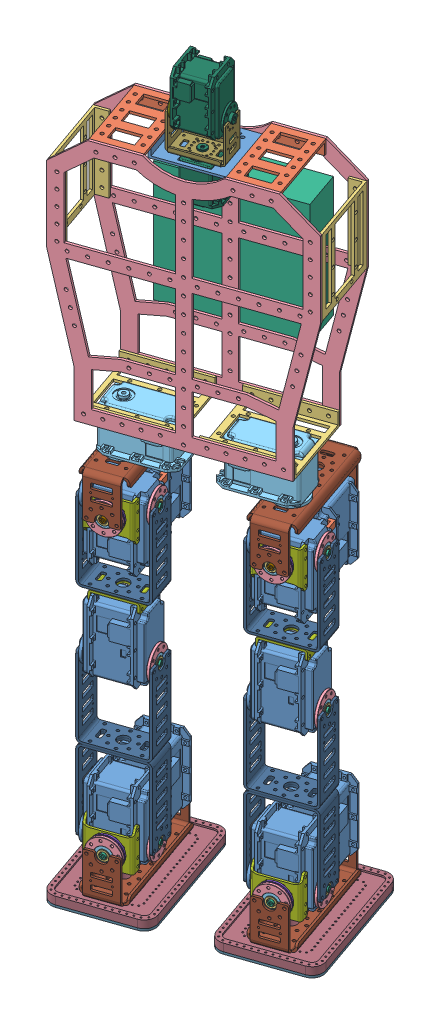
SolidWorks assembly main_new_feet_no_arm, configuration Default. Lengths in mm.
Overall size (261.31 695.74 185.95).
113 component instances, 25 part files, 43 mates.
Components (placement in the parent):
- leg_l2-1: leg_l2 [Default] at (32.8984 -224.9307 -176.674) x (0.329122 0 0.944287) z (-0.944287 0 0.329122) size (106.88 70.06 58.88)
  - MX-106T_step-1: MX-106T_step [Default] at origin size (40.2 65.92 55.3)
  - MX-106T_step-2: MX-106T_step [Default] at (-44 0 0) x (0 0 1) z (-1 0 0) size (40.2 65.92 55.3)
  - FR08-X101_2017-1: FR08-X101_2017 [Default] at (-27 -7 -17) x (0 -1 0) z (0 0 1) size (28 12.3 4.8)
  - FR08-X101_2017-2: FR08-X101_2017 [Default] at (-27 -7 17) x (0 1 0) z (0 0 -1) size (28 12.3 4.8)
  - RX64-CAP_2017-1: RX64-CAP_2017 [Default] at (0 0 -25.78) x (0.56381 0.825904 0) z (0 0 -1) size (9.5 9.5 2.2)
  - HN05-I101_2017-1: HN05-I101_2017 [Default] at (0 0 -26.02) x (0.824833 -0.565376 0) z (0.565376 0.824833 0) size (28 3.77 28)
  - MF128ZZ_2017-1: MF128ZZ_2017 [Default] at (0 0 -22.3) x (-0.923728 -0.383049 0) z (0.383049 -0.923728 0) size (14 3.48 14)
  - WB_M2.5X8_2017-1: WB_M2.5X8_2017 [Default] at (0 0 -28.08) x (0 0 1) z (0.825904 -0.56381 0) size (5.5 4.5 4.5)
  - FR05-S101_2017-1: FR05-S101_2017 [Default] at (24 0 0) x (0 1 0) z (0 0 1) size (36 9.31 38.02)
  - FR05-F101_2017-1: FR05-F101_2017 [Default] at (24 0 0) x (0 -0.707107 0.707107) z (1 0 0) size (27 27 5)
  - MF128ZZ_2017-2: MF128ZZ_2017 [Default] at (26.3 0 0) x (0 -1 0) z (0 0 1) size (14 3.48 14)
  - WB_M2.5X8_step-1: WB_M2.5X8_step [Default] at (32.08 0 0) x (-1 0 0) z (0 0.546944 0.837169) size (10.5 4.5 4.5)
  - HN05-I101_2017-2: HN05-I101_2017 [Default] at (30.02 0 0) x (0 -1 0) z (0 0 1) size (28 3.77 28)
  - RX64-CAP_2017-2: RX64-CAP_2017 [Default] at (29.78 0 0) x (0 0.837169 -0.546944) z (1 0 0) size (9.5 9.5 2.2)
- leg_l3-2: leg_l3 [Default] at (28.5454 -310.8375 -119.8421) x (0.944287 0 -0.329122) z (0 1 0) size (58.88 41.6 149.21)
  - HW-64106HXL_2017-1: HW-64106HXL_2017 [Default] at (-3.1848 38.233 13.9067) size (56 28 75)
  - FR05-S101_2017-1: FR05-S101_2017 [Default] at (22.8152 52.233 13.9067) x (0 -1 0) z (1 0 0) size (36 9.31 38.02)
  - MX-106T_step-1: MX-106T_step [Default] at (22.8152 52.233 -40.5933) x (0 1 0) z (-1 0 0) size (40.2 65.92 55.3)
  - HN05-I101_2017-1: HN05-I101_2017 [Default] at (48.8352 52.233 -40.5933) x (0 -0.637924 -0.7701) z (0 -0.7701 0.637924) size (28 3.77 28)
  - RX64-CAP_2017-1: RX64-CAP_2017 [Default] at (48.5952 52.233 -40.5933) x (0 0.837169 -0.546944) z (1 0 0) size (9.5 9.5 2.2)
  - MF128ZZ_2017-1: MF128ZZ_2017 [Default] at (45.1152 52.233 -40.5933) x (0 -0.162836 -0.986653) z (0 -0.986653 0.162836) size (14 3.48 14)
  - WB_M2.5X8_2017-1: WB_M2.5X8_2017 [Default] at (50.8952 52.233 -40.5933) x (-1 0 0) z (0 0.546944 0.837169) size (5.5 4.5 4.5)
- leg_l4-1: leg_l4 [Default] at (8.2175 -492.0992 -119.3689) x (0.944287 0 -0.329122) z (0 1 0) size (56 28 150)
  - HW-64106HXL_2017-1: HW-64106HXL_2017 [Default] at (16.1663 31.9894 68.6685) size (56 28 75)
  - HW-64106HXL_2017-2: HW-64106HXL_2017 [Default] at (68.1663 31.9894 68.6685) x (-1 0 0) z (0 0 -1) size (56 28 75)
- leg_l5-1: leg_l5 [Default] at (63.8478 -442.1127 -223.3318) x (0.89528 -0.033567 0.444237) z (-0.424558 -0.366444 0.827931) size (104.02 99.97 119.36)
  - MX-106T_step-1: MX-106T_step [Default] at (-5.1915 -29.4269 71.3073) x (-0.714144 -0.278818 -0.642073) z (-0.699193 0.240141 0.673395) size (40.2 65.92 55.3)
  - MX-106T_step-2: MX-106T_step [Default] at (-36.6138 -41.6949 43.056) x (0.699193 -0.240141 -0.673395) z (-0.714144 -0.278818 -0.642073) size (40.2 65.92 55.3)
  - FR08-X101_2017-1: FR08-X101_2017 [Default] at (-36.5946 -26.3638 62.8539) x (-0.033567 0.929835 -0.366444) z (0.699193 -0.240141 -0.673395) size (28 12.3 4.8)
  - FR08-X101_2017-2: FR08-X101_2017 [Default] at (-12.8221 -34.5286 39.9585) x (0.033567 -0.929835 0.366444) z (-0.699193 0.240141 0.673395) size (28 12.3 4.8)
  - HN05-I101_2017-1: HN05-I101_2017 [Default] at (13.0015 -35.6754 53.7855) x (0.048348 -0.923861 0.379661) z (0.713296 0.298014 0.634347) size (28 3.77 28)
  - RX64-CAP_2017-1: RX64-CAP_2017 [Default] at (12.8337 -35.6178 53.9472) x (-0.430608 0.610431 -0.664793) z (0.699193 -0.240141 -0.673395) size (9.5 9.5 2.2)
  - HN05-I101_2017-2: HN05-I101_2017 [Default] at (16.2471 -21.0568 90.5823) x (0.601193 -0.714144 -0.35856) z (-0.35856 -0.642073 0.677626) size (28 3.77 28)
  - RX64-CAP_2017-2: RX64-CAP_2017 [Default] at (16.0757 -21.1237 90.4282) x (-0.307188 0.949038 -0.070448) z (0.714144 0.278818 0.642073) size (9.5 9.5 2.2)
  - MF128ZZ_2017-1: MF128ZZ_2017 [Default] at (10.4005 -34.7821 56.2906) x (0.048348 -0.923861 0.379661) z (0.713296 0.298014 0.634347) size (14 3.48 14)
  - WB_M2.5X8_2017-1: WB_M2.5X8_2017 [Default] at (14.4419 -36.1701 52.3983) x (-0.699193 0.240141 0.673395) z (0.570706 0.754788 0.323403) size (5.5 4.5 4.5)
  - MF128ZZ_2017-2: MF128ZZ_2017 [Default] at (13.5905 -22.094 88.1938) x (0.601193 -0.714144 -0.35856) z (-0.35856 -0.642073 0.677626) size (14 3.48 14)
  - WB_M2.5X8_2017-2: WB_M2.5X8_2017 [Default] at (17.7183 -20.4824 91.905) x (-0.714144 -0.278818 -0.642073) z (-0.628994 -0.146927 0.763399) size (5.5 4.5 4.5)
  - FR05-S101_2017-1: FR05-S101_2017 [Default] at (11.948 -22.7353 86.717) x (0.033567 -0.929835 0.366444) z (0.699193 -0.240141 -0.673395) size (36 9.31 38.02)
  - FR05-F101_2017-1: FR05-F101_2017 [Default] at (11.948 -22.7353 86.717) x (0.699193 -0.240141 -0.673395) z (0.714144 0.278818 0.642073) size (27 27 5)
- HW-64106HXW_2017-3: HW-64106HXW_2017 [Default] at (141.3019 -187.9307 -286.4689) x (0.329122 0 0.944287) z (0 -1 0) size (105 37.08 40)
- leg_l2-2: leg_l2 [Default] at (148.5736 -224.9307 -216.9914) x (0.329122 0 0.944287) z (-0.944287 0 0.329122) size (106.88 70.06 58.88)
  - MX-106T_step-1: MX-106T_step [Default] at origin size (40.2 65.92 55.3)
  - MX-106T_step-2: MX-106T_step [Default] at (-44 0 0) x (0 0 1) z (-1 0 0) size (40.2 65.92 55.3)
  - FR08-X101_2017-1: FR08-X101_2017 [Default] at (-27 -7 -17) x (0 -1 0) z (0 0 1) size (28 12.3 4.8)
  - FR08-X101_2017-2: FR08-X101_2017 [Default] at (-27 -7 17) x (0 1 0) z (0 0 -1) size (28 12.3 4.8)
  - RX64-CAP_2017-1: RX64-CAP_2017 [Default] at (0 0 -25.78) x (0.56381 0.825904 0) z (0 0 -1) size (9.5 9.5 2.2)
  - HN05-I101_2017-1: HN05-I101_2017 [Default] at (0 0 -26.02) x (0.824833 -0.565376 0) z (0.565376 0.824833 0) size (28 3.77 28)
  - MF128ZZ_2017-1: MF128ZZ_2017 [Default] at (0 0 -22.3) x (-0.923728 -0.383049 0) z (0.383049 -0.923728 0) size (14 3.48 14)
  - WB_M2.5X8_2017-1: WB_M2.5X8_2017 [Default] at (0 0 -28.08) x (0 0 1) z (0.825904 -0.56381 0) size (5.5 4.5 4.5)
  - FR05-S101_2017-1: FR05-S101_2017 [Default] at (24 0 0) x (0 1 0) z (0 0 1) size (36 9.31 38.02)
  - FR05-F101_2017-1: FR05-F101_2017 [Default] at (24 0 0) x (0 -0.707107 0.707107) z (1 0 0) size (27 27 5)
  - MF128ZZ_2017-2: MF128ZZ_2017 [Default] at (26.3 0 0) x (0 -1 0) z (0 0 1) size (14 3.48 14)
  - WB_M2.5X8_step-1: WB_M2.5X8_step [Default] at (32.08 0 0) x (-1 0 0) z (0 0.546944 0.837169) size (10.5 4.5 4.5)
  - HN05-I101_2017-2: HN05-I101_2017 [Default] at (30.02 0 0) x (0 -1 0) z (0 0 1) size (28 3.77 28)
  - RX64-CAP_2017-2: RX64-CAP_2017 [Default] at (29.78 0 0) x (0 0.837169 -0.546944) z (1 0 0) size (9.5 9.5 2.2)
- leg_l3-3: leg_l3 [Default] at (144.2206 -310.8375 -160.1595) x (0.944287 0 -0.329122) z (0 1 0) size (58.88 41.6 149.21)
  - HW-64106HXL_2017-1: HW-64106HXL_2017 [Default] at (-3.1848 38.233 13.9067) size (56 28 75)
  - FR05-S101_2017-1: FR05-S101_2017 [Default] at (22.8152 52.233 13.9067) x (0 -1 0) z (1 0 0) size (36 9.31 38.02)
  - MX-106T_step-1: MX-106T_step [Default] at (22.8152 52.233 -40.5933) x (0 1 0) z (-1 0 0) size (40.2 65.92 55.3)
  - HN05-I101_2017-1: HN05-I101_2017 [Default] at (48.8352 52.233 -40.5933) x (0 -0.637924 -0.7701) z (0 -0.7701 0.637924) size (28 3.77 28)
  - RX64-CAP_2017-1: RX64-CAP_2017 [Default] at (48.5952 52.233 -40.5933) x (0 0.837169 -0.546944) z (1 0 0) size (9.5 9.5 2.2)
  - MF128ZZ_2017-1: MF128ZZ_2017 [Default] at (45.1152 52.233 -40.5933) x (0 -0.162836 -0.986653) z (0 -0.986653 0.162836) size (14 3.48 14)
  - WB_M2.5X8_2017-1: WB_M2.5X8_2017 [Default] at (50.8952 52.233 -40.5933) x (-1 0 0) z (0 0.546944 0.837169) size (5.5 4.5 4.5)
- leg_l4-2: leg_l4 [Default] at (123.8927 -492.0992 -159.6864) x (0.944287 0 -0.329122) z (0 1 0) size (56 28 150)
  - HW-64106HXL_2017-1: HW-64106HXL_2017 [Default] at (16.1663 31.9894 68.6685) size (56 28 75)
  - HW-64106HXL_2017-2: HW-64106HXL_2017 [Default] at (68.1663 31.9894 68.6685) x (-1 0 0) z (0 0 -1) size (56 28 75)
- leg_l5-2: leg_l5 [Default] at (179.523 -442.1127 -263.6493) x (0.89528 -0.033567 0.444237) z (-0.424558 -0.366444 0.827931) size (104.02 99.97 119.36)
  - MX-106T_step-1: MX-106T_step [Default] at (-5.1915 -29.4269 71.3073) x (-0.714144 -0.278818 -0.642073) z (-0.699193 0.240141 0.673395) size (40.2 65.92 55.3)
  - MX-106T_step-2: MX-106T_step [Default] at (-36.6138 -41.6949 43.056) x (0.699193 -0.240141 -0.673395) z (-0.714144 -0.278818 -0.642073) size (40.2 65.92 55.3)
  - FR08-X101_2017-1: FR08-X101_2017 [Default] at (-36.5946 -26.3638 62.8539) x (-0.033567 0.929835 -0.366444) z (0.699193 -0.240141 -0.673395) size (28 12.3 4.8)
  - FR08-X101_2017-2: FR08-X101_2017 [Default] at (-12.8221 -34.5286 39.9585) x (0.033567 -0.929835 0.366444) z (-0.699193 0.240141 0.673395) size (28 12.3 4.8)
  - HN05-I101_2017-1: HN05-I101_2017 [Default] at (13.0015 -35.6754 53.7855) x (0.048348 -0.923861 0.379661) z (0.713296 0.298014 0.634347) size (28 3.77 28)
  - RX64-CAP_2017-1: RX64-CAP_2017 [Default] at (12.8337 -35.6178 53.9472) x (-0.430608 0.610431 -0.664793) z (0.699193 -0.240141 -0.673395) size (9.5 9.5 2.2)
  - HN05-I101_2017-2: HN05-I101_2017 [Default] at (16.2471 -21.0568 90.5823) x (0.601193 -0.714144 -0.35856) z (-0.35856 -0.642073 0.677626) size (28 3.77 28)
  - RX64-CAP_2017-2: RX64-CAP_2017 [Default] at (16.0757 -21.1237 90.4282) x (-0.307188 0.949038 -0.070448) z (0.714144 0.278818 0.642073) size (9.5 9.5 2.2)
  - MF128ZZ_2017-1: MF128ZZ_2017 [Default] at (10.4005 -34.7821 56.2906) x (0.048348 -0.923861 0.379661) z (0.713296 0.298014 0.634347) size (14 3.48 14)
  - WB_M2.5X8_2017-1: WB_M2.5X8_2017 [Default] at (14.4419 -36.1701 52.3983) x (-0.699193 0.240141 0.673395) z (0.570706 0.754788 0.323403) size (5.5 4.5 4.5)
  - MF128ZZ_2017-2: MF128ZZ_2017 [Default] at (13.5905 -22.094 88.1938) x (0.601193 -0.714144 -0.35856) z (-0.35856 -0.642073 0.677626) size (14 3.48 14)
  - WB_M2.5X8_2017-2: WB_M2.5X8_2017 [Default] at (17.7183 -20.4824 91.905) x (-0.714144 -0.278818 -0.642073) z (-0.628994 -0.146927 0.763399) size (5.5 4.5 4.5)
  - FR05-S101_2017-1: FR05-S101_2017 [Default] at (11.948 -22.7353 86.717) x (0.033567 -0.929835 0.366444) z (0.699193 -0.240141 -0.673395) size (36 9.31 38.02)
  - FR05-F101_2017-1: FR05-F101_2017 [Default] at (11.948 -22.7353 86.717) x (0.699193 -0.240141 -0.673395) z (0.714144 0.278818 0.642073) size (27 27 5)
- HW-64106HXW_2017-5: HW-64106HXW_2017 [Default] at (25.6267 -187.9307 -246.1515) x (0.329122 0 0.944287) z (0 -1 0) size (105 37.08 40)
- FR07-H101K-1: FR07-H101K [Default] at (93.0399 76.5333 -190.2227) x (-0.944287 0 0.329122) z (0 1 0) size (44 26 32.5)
- leg_l6_new_feet-1: leg_l6_new_feet [Default] at (87.7926 -593.8701 -169.2992) x (-0.329122 0 -0.944287) z (0 1 0) size (120 80 47.5)
  - HW-64106HXW_2017-1: HW-64106HXW_2017 [Default] at (-3.9692 33.4087 61.4394) size (105 37.08 40)
  - foot_new-1: foot_new [Default] at (44.5308 49.4087 55.9394) x (1 0 0) z (0 -1 0) size (120 7 80)
  - Part4^leg_l6_new_feet-1: Part4^leg_l6_new_feet [Default] at (44.5308 49.4087 55.9394) x (-1 0 0) z (0 0 -1) size (120 80 2) (virtual)
- leg_l6_new_feet-2: leg_l6_new_feet [Default] at (203.4678 -593.8701 -209.6167) x (-0.329122 0 -0.944287) z (0 1 0) size (120 80 47.5)
  - HW-64106HXW_2017-1: HW-64106HXW_2017 [Default] at (-3.9692 33.4087 61.4394) size (105 37.08 40)
  - foot_new-1: foot_new [Default] at (44.5308 49.4087 55.9394) x (1 0 0) z (0 -1 0) size (120 7 80)
  - Part4^leg_l6_new_feet-1: Part4^leg_l6_new_feet [Default] at (44.5308 49.4087 55.9394) x (-1 0 0) z (0 0 -1) size (120 80 2) (virtual)
- head_2_no_camera-1: head_2_no_camera [Default] at (57.4956 210.3096 -243.8587) x (0.944287 0 -0.329122) z (0.329122 0 0.944287) size (44.45 51.16 35.6)
  - MX28_step-1: MX28_step [Default] at (-26.9298 -63.9825 50.4384) x (0 0 1) z (1 0 0) size (35.6 50.71 42.6)
  - MX28_HN07-i101-1: MX28_HN07-i101 [Default] at (-4.5387 -101.2764 62.3462) x (0 0.153917 -0.988084) z (0 0.988084 0.153917) size (22 3.05 22)
  - MF106ZZ-1: MF106ZZ [Défaut] at (-4.3887 -101.2764 62.3462) x (0 0.577041 0.816715) z (0 0.816715 -0.577041) size (11.2 3 11.2)
  - RX28-CAP-1: RX28-CAP [Défaut] at (-4.3887 -101.2764 62.3462) x (0 1 0) z (-1 0 0) size (7.2 7.2 1.8)
- torso_no_arm_motor-1: torso_no_arm_motor [Default] at (90.5715 74.6103 -197.3049) x (0.944287 0 -0.329122) z (0.329122 0 0.944287) size (200 273.5 112.95)
  - torso_frame_head-1: torso_frame_head [Default] at (0 -3.827 -35) size (76 8 58.5)
  - torso_frame_link-1: torso_frame_link [Default] at (-50 -6.241 0) x (0 0 1) z (-1 0 0) size (75.11 12.7 53.47)
  - torso_frame_motor-1: torso_frame_motor [Default] at (-98.857 -88.541 0) x (0 0 1) z (-1 0 0) size (68 70 36.25)
  - torso_main-1: torso_main [Default] at (0 0 34) size (200 228.5 2.29)
  - torso_main-2: torso_main [Default] at (0 0 -36.286) size (200 228.5 2.29)
  - torso_frame_link-2: torso_frame_link [Default] at (50 -6.241 0) x (0 0 1) z (-1 0 0) size (75.11 12.7 53.47)
  - torso_frame_motor-2: torso_frame_motor [Default] at (98.857 -88.541 0) x (0 0 -1) z (1 0 0) size (68 70 36.25)
  - torso_frame_motor-3: torso_frame_motor [Default] at (10 -220.898 0) x (0 0 -1) z (0 -1 0) size (68 70 36.25)
  - torso_frame_motor-4: torso_frame_motor [Default] at (-10 -220.898 0) x (0 0 1) z (0 -1 0) size (68 70 36.25)
  - MX-64T_step-3: MX-64T_step [Default] at (61.25 -239.041 0) x (0 0 -1) z (0 -1 0) size (40.2 62.1 50)
  - MX-64T_step-4: MX-64T_step [Default] at (-61.25 -239.041 0) x (0 0 1) z (0 -1 0) size (40.2 62.1 50)
  - MX28_step-1: MX28_step [Default] at (11.9078 -61.4181 -29.7938) x (-1 0 0) z (0 1 0) size (35.6 50.71 42.6)
  - nuc-1: nuc [Default] at (0 -108.0269 -54.066) size (114.3 111.76 35.56)
- Part1^main_new_feet_no_arm-1: Part1^main_new_feet_no_arm [Default] at origin (virtual)
Mates (geometry in assembly coordinates):
- Concentric3: concentric anti-aligned: cylinder of leg_l2-1/HN05-I101_2017-1 through (57.4688 -224.9307 -185.2377) axis (-0.944287 0 0.329122) radius 14; cylinder of leg_l3-2/HW-64106HXL_2017-1 through (59.3385 -224.9307 -185.8894) axis (0.944287 0 -0.329122) radius 5.1
- Concentric4: concentric anti-aligned: cylinder of leg_l3-2/HN05-I101_2017-1 through (57.4688 -351.4307 -185.2377) axis (-0.944287 0 0.329122) radius 14; cylinder of leg_l4-1/HW-64106HXL_2017-1 through (59.3385 -351.4307 -185.8894) axis (0.944287 0 -0.329122) radius 5.1
- Concentric5: concentric anti-aligned: cylinder of leg_l4-1/HW-64106HXL_2017-2 through (6.4584 -495.4307 -167.4586) axis (-0.944287 0 0.329122) radius 5.1; cylinder of leg_l5-1/MX-106T_step-1 through (3.4461 -495.4307 -166.4087) axis (0.944287 0 -0.329122) radius 5
- Coincident5: coincident anti-aligned: plane of leg_l4-1/HW-64106HXL_2017-2 through (8.347 -495.4307 -168.1168) normal (0.944287 0 -0.329122); plane of leg_l5-1/MX-106T_step-1 through (8.347 -495.4307 -168.1168) normal (-0.944287 0 0.329122)
- Coincident6: coincident anti-aligned: plane of leg_l2-1/MX-106T_step-1 through (8.347 -224.9307 -168.1168) normal (-0.944287 0 0.329122); plane of leg_l3-2/HW-64106HXL_2017-1 through (8.347 -224.9307 -168.1168) normal (0.944287 0 -0.329122)
- Coincident7: coincident anti-aligned: plane of leg_l2-1/MX-106T_step-1 through (8.347 -224.9307 -168.1168) normal (-0.944287 0 0.329122); plane of leg_l3-2/HW-64106HXL_2017-1 through (8.347 -224.9307 -168.1168) normal (0.944287 0 -0.329122)
- Coincident8: coincident anti-aligned: plane of leg_l3-2/MX-106T_step-1 through (8.347 -351.4307 -168.1168) normal (-0.944287 0 0.329122); plane of leg_l4-1/HW-64106HXL_2017-1 through (8.347 -351.4307 -168.1168) normal (0.944287 0 -0.329122)
- Concentric8: concentric aligned: cylinder of HW-64106HXW_2017-3 through (159.4347 -224.9307 -185.83) axis (0.329122 0 0.944287) radius 5.1; cylinder of leg_l2-2/MX-106T_step-2 through (123.8269 -224.9307 -287.9924) axis (0.329122 0 0.944287) radius 5
- Coincident11: coincident anti-aligned: plane of HW-64106HXW_2017-3 through (125.5351 -210.0147 -283.0916) normal (0.329122 0 0.944287); plane of leg_l2-2/MX-106T_step-2 through (125.5351 -224.9307 -283.0916) normal (-0.329122 0 -0.944287)
- Concentric9: concentric aligned: cylinder of leg_l2-2/MX-106T_step-1 through (119.1213 -224.9307 -206.7261) axis (0.944287 0 -0.329122) radius 5; cylinder of leg_l3-3/HW-64106HXL_2017-1 through (124.0222 -224.9307 -208.4343) axis (0.944287 0 -0.329122) radius 5.1
- Coincident12: coincident anti-aligned: plane of leg_l2-2/MX-106T_step-1 through (124.0222 -224.9307 -208.4343) normal (-0.944287 0 0.329122); plane of leg_l3-3/HW-64106HXL_2017-1 through (124.0222 -224.9307 -208.4343) normal (0.944287 0 -0.329122)
- Concentric10: concentric aligned: cylinder of leg_l3-3/MX-106T_step-1 through (119.1213 -351.4307 -206.7261) axis (0.944287 0 -0.329122) radius 5; cylinder of leg_l4-2/HW-64106HXL_2017-1 through (124.0222 -351.4307 -208.4343) axis (0.944287 0 -0.329122) radius 5.1
- Coincident13: coincident anti-aligned: plane of leg_l3-3/MX-106T_step-1 through (124.0222 -351.4307 -208.4343) normal (-0.944287 0 0.329122); plane of leg_l4-2/HW-64106HXL_2017-1 through (124.0222 -351.4307 -208.4343) normal (0.944287 0 -0.329122)
- Concentric13: concentric anti-aligned: cylinder of leg_l4-2/HW-64106HXL_2017-2 through (122.1336 -495.4307 -207.776) axis (-0.944287 0 0.329122) radius 5.1; cylinder of leg_l5-2/MX-106T_step-1 through (119.1213 -495.4307 -206.7261) axis (0.944287 0 -0.329122) radius 5
- Coincident16: coincident anti-aligned: plane of leg_l4-2/HW-64106HXL_2017-2 through (124.0222 -495.4307 -208.4343) normal (0.944287 0 -0.329122); plane of leg_l5-2/MX-106T_step-1 through (124.0222 -495.4307 -208.4343) normal (-0.944287 0 0.329122)
- Parallel3: parallel anti-aligned: plane of leg_l2-1/MX-106T_step-1 through (32.8984 -224.9307 -176.674) normal (0.329122 0 0.944287); plane of leg_l3-2/HW-64106HXL_2017-1 through (12.9547 -296.9307 -154.8968) normal (-0.329122 0 -0.944287)
- Parallel4: parallel aligned: plane of leg_l3-2/MX-106T_step-1 through (32.8984 -351.4307 -176.674) normal (-0.329122 0 -0.944287); plane of leg_l4-1/HW-64106HXL_2017-1 through (12.9547 -423.4307 -154.8968) normal (-0.329122 0 -0.944287)
- Parallel5: parallel aligned: plane of leg_l4-1/HW-64106HXL_2017-2 through (62.0576 -423.4307 -172.0111) normal (-0.329122 0 -0.944287); plane of leg_l5-1/MX-106T_step-1 through (32.8984 -495.4307 -176.674) normal (-0.329122 0 -0.944287)
- Parallel8: parallel aligned: plane of HW-64106HXW_2017-3 through (141.3019 -187.9307 -286.4689) normal (-0.944287 0 0.329122); plane of leg_l2-2/MX-106T_step-1 through (148.5736 -224.9307 -216.9914) normal (-0.944287 0 0.329122)
- Parallel9: parallel anti-aligned: plane of leg_l2-2/MX-106T_step-1 through (148.5736 -224.9307 -216.9914) normal (0.329122 0 0.944287); plane of leg_l3-3/HW-64106HXL_2017-1 through (128.6299 -296.9307 -195.2142) normal (-0.329122 0 -0.944287)
- Parallel10: parallel aligned: plane of leg_l3-3/MX-106T_step-1 through (148.5736 -351.4307 -216.9914) normal (-0.329122 0 -0.944287); plane of leg_l4-2/HW-64106HXL_2017-1 through (128.6299 -423.4307 -195.2142) normal (-0.329122 0 -0.944287)
- Parallel11: parallel aligned: plane of leg_l4-2/HW-64106HXL_2017-2 through (177.7328 -423.4307 -212.3286) normal (-0.329122 0 -0.944287); plane of leg_l5-2/MX-106T_step-1 through (148.5736 -495.4307 -216.9914) normal (-0.329122 0 -0.944287)
- Concentric19: concentric aligned: cylinder of leg_l2-1/MX-106T_step-2 through (8.1517 -224.9307 -247.6749) axis (0.329122 0 0.944287) radius 5; cylinder of HW-64106HXW_2017-5 through (43.7595 -224.9307 -145.5125) axis (0.329122 0 0.944287) radius 5.1
- Coincident39: coincident anti-aligned: plane of leg_l2-1/MX-106T_step-2 through (9.8599 -224.9307 -242.7741) normal (-0.329122 0 -0.944287); plane of HW-64106HXW_2017-5 through (9.8599 -210.0147 -242.7741) normal (0.329122 0 0.944287)
- Parallel18: parallel aligned: plane of leg_l2-1/MX-106T_step-1 through (32.8984 -224.9307 -176.674) normal (-0.944287 0 0.329122); plane of HW-64106HXW_2017-5 through (25.6267 -187.9307 -246.1515) normal (-0.944287 0 0.329122)
- Concentric34: concentric anti-aligned: cylinder of FR07-H101K-1 through (72.2656 109.0333 -182.982) axis (0.944287 0 -0.329122) radius 4; cylinder of head_2_no_camera-1/MX28_step-1 through (115.3652 109.0333 -198.004) axis (-0.944287 0 0.329122) radius 11
- Concentric35: concentric aligned: cylinder of FR07-H101K-1 through (93.0399 78.0333 -190.2227) axis (0 -1 0) radius 4; cylinder of torso_no_arm_motor-1/MX28_step-1 through (93.0399 79.6758 -190.2227) axis (0 -1 0) radius 4
- Coincident59: coincident anti-aligned: plane of FR07-H101K-1 through (93.0399 76.5333 -190.2227) normal (0 -1 0); plane of torso_no_arm_motor-1/MX28_step-1 through (93.0399 76.5333 -190.2227) normal (0 1 0)
- Concentric36: concentric anti-aligned: cylinder of HW-64106HXW_2017-5 through (32.7339 -306.252 -177.1461) axis (0 -1 0) radius 5.1; cylinder of torso_no_arm_motor-1/MX-64T_step-4 through (32.7339 -192.8057 -177.1461) axis (0 1 0) radius 14
- Coincident61: coincident anti-aligned: plane of HW-64106HXW_2017-5 through (34.7909 -187.9307 -171.2443) normal (0 1 0); plane of torso_no_arm_motor-1/MX-64T_step-4 through (32.7339 -187.9307 -177.1461) normal (0 -1 0)
- Parallel32: parallel aligned: plane of HW-64106HXW_2017-5 through (8.9735 -191.5147 -188.9857) normal (-0.944287 0 0.329122); plane of torso_no_arm_motor-1/MX-64T_step-4 through (25.2304 -143.9307 -159.1754) normal (-0.944287 0 0.329122)
- Concentric37: concentric anti-aligned: cylinder of HW-64106HXW_2017-3 through (148.4091 -306.252 -217.4636) axis (0 -1 0) radius 5.1; cylinder of torso_no_arm_motor-1/MX-64T_step-3 through (148.4091 -192.8057 -217.4636) axis (0 1 0) radius 14
- Coincident63: coincident anti-aligned: plane of HW-64106HXW_2017-3 through (150.4661 -187.9307 -211.5618) normal (0 1 0); plane of torso_no_arm_motor-1/MX-64T_step-3 through (148.4091 -187.9307 -217.4636) normal (0 -1 0)
- Parallel33: parallel aligned: plane of HW-64106HXW_2017-3 through (159.6628 -191.5147 -241.507) normal (0.944287 0 -0.329122); plane of torso_no_arm_motor-1/MX-64T_step-3 through (155.9125 -143.9307 -235.4343) normal (0.944287 0 -0.329122)
- Concentric38: concentric anti-aligned: cylinder of leg_l5-1/HN05-I101_2017-2 through (42.7787 -495.4307 -148.3265) axis (-0.329122 0 -0.944287) radius 14; circle of leg_l6_new_feet-1/HW-64106HXW_2017-1
- Parallel34: parallel aligned: plane of leg_l5-1/MX-106T_step-1 through (49.8448 -509.9307 -197.936) normal (0 -1 0); plane of leg_l6_new_feet-1/foot_new-1 through (26.4806 -537.9307 -195.0876) normal (0 -1 0)
- Concentric39: concentric aligned: cylinder of leg_l5-2/HN05-I101_2017-2 through (158.4539 -495.4307 -188.6439) axis (-0.329122 0 -0.944287) radius 14; cylinder of leg_l6_new_feet-2/HW-64106HXW_2017-1 through (124.8768 -495.4307 -284.9801) axis (-0.329122 0 -0.944287) radius 5.1
- Parallel35: parallel aligned: plane of leg_l5-2/MX-106T_step-1 through (165.52 -509.9307 -238.2534) normal (0 -1 0); plane of leg_l6_new_feet-2/foot_new-1 through (142.1558 -537.9307 -235.405) normal (0 -1 0)
- Coincident70: coincident anti-aligned: plane of leg_l5-1/MX-106T_step-2 through (9.8599 -495.4307 -242.7741) normal (-0.329122 0 -0.944287); plane of leg_l6_new_feet-1/HW-64106HXW_2017-1 through (9.8599 -510.3468 -242.7741) normal (0.329122 0 0.944287)
- Coincident71: coincident anti-aligned: plane of leg_l5-2/MX-106T_step-2 through (125.5351 -495.4307 -283.0916) normal (-0.329122 0 -0.944287); plane of leg_l6_new_feet-2/HW-64106HXW_2017-1 through (125.5351 -510.3468 -283.0916) normal (0.329122 0 0.944287)
- Coincident72: coincident anti-aligned: plane of FR07-H101K-1 through (112.3978 109.0333 -196.9697) normal (-0.944287 0 0.329122); plane of head_2_no_camera-1/MX28_step-1 through (112.3978 109.0333 -196.9697) normal (0.944287 0 -0.329122)
- Parallel36: parallel aligned: plane of head_2_no_camera-1/MX28_step-1 through (86.3865 141.6333 -169.0535) normal (0.329122 0 0.944287); plane of FR07-H101K-1 through (77.3023 76.5333 -173.0885) normal (0.329122 0 0.944287)
- Parallel37: parallel aligned: plane of FR07-H101K-1 through (77.3023 76.5333 -173.0885) normal (0.329122 0 0.944287); plane of torso_no_arm_motor-1/torso_main-1 through (102.514 114.6103 -163.0404) normal (0.329122 0 0.944287)
